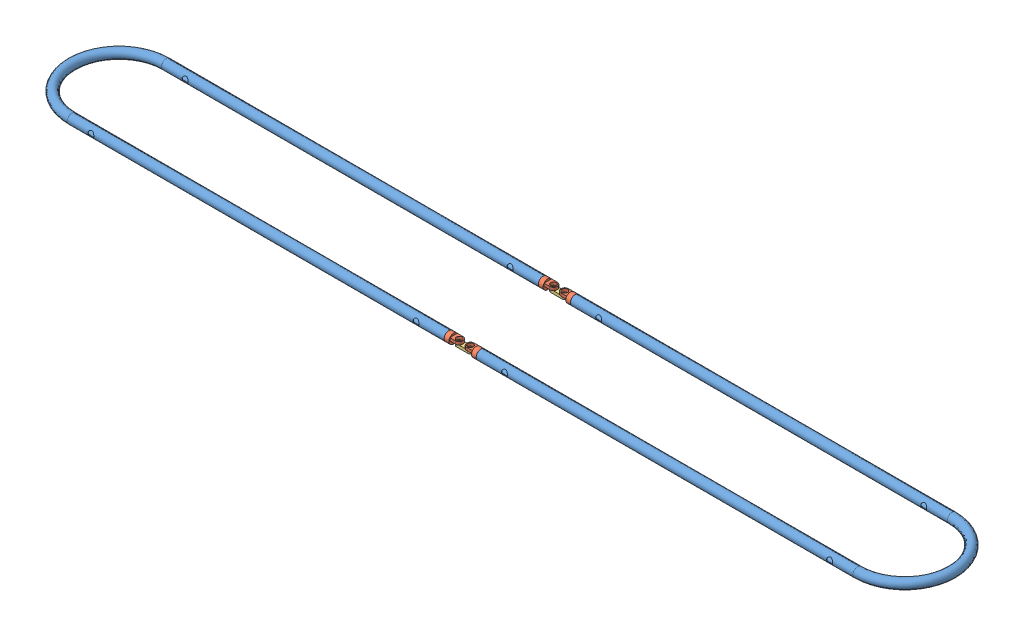
SolidWorks assembly FrameOneSideNoAnim, configuration Default. Lengths in mm.
Overall size (1488 20 220).
8 component instances, 3 part files, 7 mates.
Components (placement in the parent):
- F1-1: F1 [Default<As Welded>] at (120.0879 35.9229 252.3231) size (710 20 220)
- H1-1: H1 [Default] at (120.0879 35.9229 252.3231) x (0 1 0) z (-1 0 0) size (20 20 40)
- H2-1: H2 [Default] at (166.0879 29.9229 252.3231) x (1 0 0) z (0 1 0) size (36 12 6)
- H1-2: H1 [Default] at (188.0879 35.9229 252.3231) x (0 1 0) z (1 0 0) size (20 20 40)
- H2-2: H2 [Default] at (166.0879 29.9229 52.3231) x (1 0 0) z (0 1 0) size (36 12 6)
- H1-4: H1 [Default] at (188.0879 35.9229 52.3231) x (0 1 0) z (1 0 0) size (20 20 40)
- H1-6: H1 [Default] at (120.0879 35.9229 52.3231) x (0 1 0) z (-1 0 0) size (20 20 40)
- F1-2: F1 [Default<As Welded>] at (188.0879 35.9229 52.3231) x (-1 0 0) z (0 0 -1) size (710 20 220)
Mates (geometry in assembly coordinates):
- Hinge1: hinge = 0 rad: line of assembly; plane of assembly; line of assembly; plane of assembly; plane of assembly; plane of assembly; line of F1-1 through (-479.9121 35.9229 252.3231) axis (1 0 0); line of H1-1 through (110.0879 35.9229 252.3231) axis (1 0 0); plane of H1-1 through (120.0879 35.9229 252.3231) normal (-1 0 0); plane of F1-1 through (120.0879 35.9229 252.3231) normal (0 0 1); plane of F1-1 through (120.0879 35.9229 252.3231) normal (0 1 0); plane of H1-1 through (120.0879 35.9229 252.3231) normal (1 0 0)
- Hinge2: hinge = 0.702677 rad: line of assembly; plane of assembly; line of assembly; plane of assembly; plane of assembly; plane of assembly; line of H2-1 through (142.0879 35.9229 252.3231) axis (0 -1 0); line of H1-1; plane of H2-1; plane of H1-1 through (150.0879 35.9229 262.3231) normal (0 -1 0); plane of H2-1 through (166.0879 29.9229 252.3231) normal (0 0 -1); plane of H1-1 through (120.0879 35.9229 252.3231) normal (0 0 -1)
- Hinge3: hinge = 2.438865 rad: line of assembly; plane of assembly; line of assembly; plane of assembly; plane of assembly; plane of assembly; line of H1-2 through (166.0879 35.9229 252.3231) axis (0 1 0); line of H2-1; plane of H1-2; plane of H2-1 through (142.0879 35.9229 252.3231) normal (0 1 0); plane of H1-2 through (188.0879 35.9229 252.3231) normal (0 0 1); plane of H2-1 through (166.0879 29.9229 252.3231) normal (0 0 -1)
- Hinge4: hinge: line of assembly; plane of assembly; line of assembly; plane of assembly; line of H1-6 through (110.0879 35.9229 52.3231) axis (1 0 0); line of F1-1 through (120.0879 35.9229 52.3231) axis (-1 0 0); plane of F1-1 through (120.0879 35.9229 52.3231) normal (1 0 0); plane of H1-6 through (120.0879 35.9229 52.3231) normal (-1 0 0)
- Hinge5: hinge: line of assembly; plane of assembly; line of assembly; plane of assembly; line of H2-2 through (142.0879 35.9229 52.3231) axis (0 -1 0); line of H1-6; plane of H2-2; plane of H1-6 through (150.0879 35.9229 62.3231) normal (0 -1 0)
- Hinge6: hinge: line of assembly; plane of assembly; line of assembly; plane of assembly; line of H1-4 through (198.0879 35.9229 52.3231) axis (-1 0 0); line of F1-2; plane of H1-4; plane of F1-2 through (188.0879 35.9229 52.3231) normal (-1 0 0)
- Coincident14: coincident: line of H1-2 through (198.0879 35.9229 252.3231) axis (-1 0 0); line of F1-2 through (188.0879 35.9229 252.3231) axis (1 0 0)
